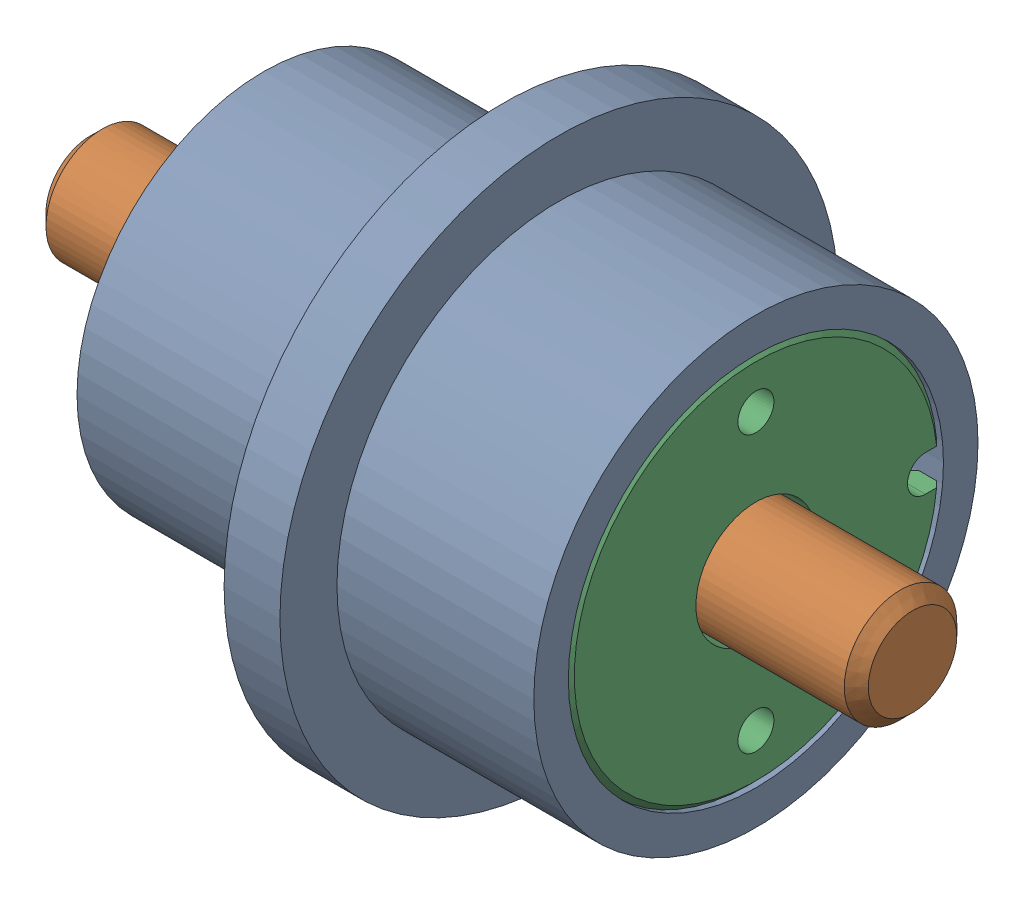
SolidWorks assembly Ferrotec SS-188-SLEX (103073), configuration Default. Lengths in mm.
Overall size (34.8 23.62 23.62).
4 component instances, 4 part files, 0 mates.
Components (placement in the parent):
- 101920 render-1: 101920 render [Default] at origin size (20.83 23.62 23.62)
- 116906 render-1: 116906 render [Default] at (-7.3406 0 0) size (34.8 4.76 4.76)
- 101649 render-1: 101649 render [Default] at (19.558 0 0) size (1.27 15.88 15.84)
- 100517 render-1: 100517 render [Default] at origin size (1.78 19.38 19.38)
